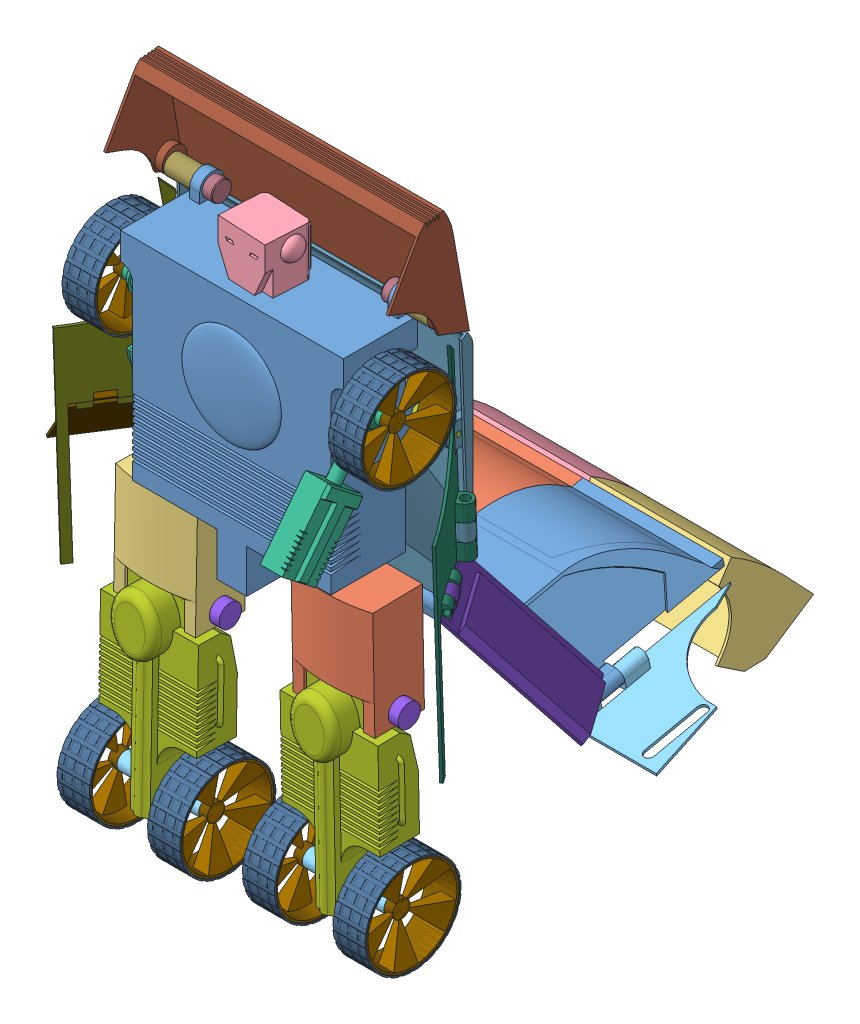
SolidWorks assembly TransformerX_MainAssembly, configuration Default. Lengths in mm.
Overall size (220.06 268.06 212.85).
45 component instances, 25 part files, 124 mates.
Components (placement in the parent):
- Body-1: Body [Default] at (46.3768 50.8704 65.1566) size (90 111.5 41.19)
- Leg2_left-1: Leg2_left [Default] at (81.8768 16.1749 64.6855) x (1 0 0) z (0 -0.019227 0.999815) size (33 44.2 22.31)
- Leg2_right-1: Leg2_right [Default] at (10.8768 16.1749 65.6276) x (1 0 0) z (0 0.019227 0.999815) size (33 44.2 22.31)
- Head-1: Head [Default] at (46.3768 135.8704 65.1566) x (0.998497 0 0.054809) z (-0.054809 0 0.998497) size (26 20 18.29)
- Axis-1: Axis [Default] at (81.8768 8.9762 64.5471) x (0 0 1) z (-1 0 0) size (7 7 39)
- Axis-2: Axis [Default] at (10.8768 8.9762 65.7661) x (0 -0.784262 0.62043) z (-1 0 0) size (7 7 39)
- Arm-4: Arm [Default] at (1.8768 75.0914 61.5517) x (-1 0 0) z (0 0.191408 -0.981511) size (24 60 17)
- Arm-5: Arm [Default] at (90.8768 82.5325 92.8919) x (1 0 0) z (0 0.612187 0.790713) size (24 60 17)
- Leg1-1: Leg1 [Default] at (81.8768 -15.6961 68.0734) x (1 0 0) z (0 -0.019227 0.999815) size (44.5 80.02 25)
- Leg1-2: Leg1 [Default] at (10.8768 -15.5423 70.2383) x (1 0 0) z (0 0.019227 0.999815) size (44.5 80.02 25)
- Axis-3: Axis [Default] at (10.8768 -57.4346 71.0439) x (0 -0.957762 -0.287561) z (-1 0 0) size (7 7 39)
- Axis-4: Axis [Default] at (81.8768 -57.5884 67.2678) x (0 -0.784262 0.62043) z (-1 0 0) size (7 7 39)
- Locker-1: Locker [Default] at (98.3768 8.9762 64.5471) x (0 0.219799 -0.975545) z (1 0 0) size (9 9 4)
- Locker-2: Locker [Default] at (-5.6232 8.9762 65.7661) x (0 -0.568495 0.822687) z (-1 0 0) size (9 9 4)
- Locker-3: Locker [Default] at (27.3768 8.9762 65.7661) x (0 0.855004 -0.518621) z (1 0 0) size (9 9 4)
- Locker-4: Locker [Default] at (65.3768 8.9762 64.5471) x (0 -0.128282 -0.991738) z (-1 0 0) size (9 9 4)
- Wheel-1: Wheel [Default] at (-7.3732 -57.4346 71.0439) x (0 0.703889 0.71031) z (-1 0 0) size (37.5 37.5 12.5)
- Wheel-2: Wheel [Default] at (29.1268 -57.4346 71.0439) x (0 0.151949 0.988388) z (1 0 0) size (37.5 37.5 12.5)
- Wheel-3: Wheel [Default] at (63.6268 -57.5884 67.2678) x (0 -0.151949 -0.988388) z (-1 0 0) size (37.5 37.5 12.5)
- Wheel-4: Wheel [Default] at (100.1268 -57.5884 67.2678) x (0 0.151949 0.988388) z (1 0 0) size (37.5 37.5 12.5)
- Wheel-5: Wheel [Default] at (100.1268 113.3704 69.0166) x (0 0.145658 0.989335) z (1 0 0) size (37.5 37.5 12.5)
- Wheel-6: Wheel [Default] at (-7.3732 113.3704 69.0166) x (0 -0.858748 -0.512398) z (-1 0 0) size (37.5 37.5 12.5)
- Tire-1: Tire [Default] at (63.6268 -57.5884 67.2678) x (0 0.242577 -0.970132) z (1 0 0) size (38.8 38.79 13)
- Tire-2: Tire [Default] at (-7.3732 -57.4346 71.0439) x (0 0.997611 -0.069083) z (1 0 0) size (38.8 38.79 13)
- Tire-3: Tire [Default] at (29.1268 -57.4346 71.0439) x (0 -0.476218 0.879327) z (-1 0 0) size (38.8 38.79 13)
- Tire-4: Tire [Default] at (-7.3732 113.3704 69.0166) x (0 -0.247928 -0.968779) z (1 0 0) size (38.8 38.79 13)
- Tire-5: Tire [Default] at (100.1268 -57.5884 67.2678) x (0 -0.242577 0.970132) z (-1 0 0) size (38.8 38.79 13)
- Tire-6: Tire [Default] at (100.1268 113.3704 69.0166) x (0 0.041073 0.999156) z (-1 0 0) size (38.8 38.79 13)
- CarPart1-1: CarPart1 [Default] at (46.3768 147.7514 56.6059) x (0 0.939693 -0.34202) z (-1 0 0) size (40.79 38 115)
- Axis3-1: Axis3 [Default] at (92.1268 139.8704 50.1566) x (0 0 -1) z (1 0 0) size (8 8 19.5)
- Axis3-2: Axis3 [Default] at (0.6268 139.8704 50.1566) x (0 0.924225 0.381849) z (-1 0 0) size (8 8 19.5)
- Locker2-2: Locker2 [Default] at (10.3768 139.8704 50.1566) x (0 0.082275 0.99661) z (-1 0 0) size (8 8 4)
- Locker2-3: Locker2 [Default] at (82.3768 139.8704 50.1566) x (0 -0.889675 -0.456595) z (1 0 0) size (8 8 4)
- CarPart2-1: CarPart2 [Default] at (46.3768 67.0428 42.5993) x (0 0.999342 0.03628) z (-1 0 0) size (131.64 36.94 126)
- CarPart3_left-1: CarPart3_left [Default] at (119.7728 56.3074 69.5671) x (0 0.999342 0.03628) z (-0.818887 -0.020823 0.573576) size (132.4 36.62 6.5)
- CarPart3_right-1: CarPart3_right [Default] at (-27.0191 56.3074 69.5671) x (0 0.999342 0.03628) z (-0.818887 0.020823 -0.573576) size (132.4 36.62 6.5)
- CarPart_Door_left-1: CarPart_Door_left [Default] at (128.5766 36.22 44.9935) x (-0.579043 0.691915 0.431235) z (-0.579039 -0.721368 0.379924) size (59.5 53.92 22.75)
- CarPart_Door_right-1: CarPart_Door_right [Default] at (-35.2438 35.4986 45.3735) x (0.579041 0.691917 0.431234) z (-0.579041 0.721365 -0.379926) size (59.5 53.92 22.75)
- CarPart4_left-1: CarPart4_left [Default] at (74.6268 -9.0217 -28.6009) x (0 -0.208452 0.978033) z (-1 0 0) size (78.5 35.5 63)
- CarPart4_right-1: CarPart4_right [Default] at (18.1268 -9.0217 -28.6009) x (0 -0.208452 0.978033) z (-1 0 0) size (78.5 35.5 63)
- CarPart5_left-1: CarPart5_left [Default] at (74.6268 -10.0267 -75.1362) x (0 -0.554061 -0.832476) z (1 0 0) size (48.5 32.62 56.5)
- CarPart5_right-1: CarPart5_right [Default] at (18.1268 -10.0267 -75.1362) x (0 -0.554061 -0.832476) z (1 0 0) size (48.5 32.62 56.5)
- CarPart6_left-1: CarPart6_left [Default] at (122.1868 -15.3268 -30.2004) x (0 -0.208452 0.978033) z (0 -0.978033 -0.208452) size (69 37.62 7.5)
- CarPart6_right-1: CarPart6_right [Default] at (-29.4332 -16.3049 -30.4088) x (0 -0.208452 0.978033) z (0 0.978033 0.208452) size (69 37.62 7.5)
- Axis4-1: Axis4 [Default] at (46.3768 97.8704 45.1566) x (0 0 1) z (-1 0 0) size (5.5 5.5 113)
Mates (geometry in assembly coordinates):
- Concentric1: concentric aligned: cylinder of Body-1 through (74.3768 40.6704 65.1566) axis (-1 0 0) radius 3.5; cylinder of Leg2_left-1 through (74.3768 40.6704 65.1566) axis (-1 0 0) radius 3.5
- Coincident1: coincident anti-aligned: plane of Body-1 through (74.3768 40.6704 65.1566) normal (1 0 0); plane of Leg2_left-1 through (74.3768 40.6704 65.1566) normal (-1 0 0)
- Concentric2: concentric aligned: cylinder of Body-1 through (18.3768 40.6704 65.1566) axis (1 0 0) radius 3.5; cylinder of Leg2_right-1 through (18.3768 40.6704 65.1566) axis (1 0 0) radius 3.5
- Coincident2: coincident anti-aligned: plane of Body-1 through (18.3768 40.6704 65.1566) normal (-1 0 0); plane of Leg2_right-1 through (18.3768 40.6704 65.1566) normal (1 0 0)
- Parallel1: parallel aligned: plane of Leg2_left-1 through (65.3768 48.1704 55.1566) normal (0 0 -1); plane of Leg2_right-1 through (-5.6232 48.1704 55.1566) normal (0 0 -1)
- Parallel2: parallel aligned: plane of Body-1 through (91.3768 135.8704 50.1566) normal (0 0 -1); plane of Leg2_right-1
- Concentric3: concentric aligned: cylinder of Body-1 through (46.3768 142.8704 65.1566) axis (0 -1 0) radius 4.5; cylinder of Head-1 through (46.3768 142.8704 65.1566) axis (0 -1 0) radius 4.5
- Coincident5: coincident anti-aligned: plane of Body-1 through (46.3768 142.8704 65.1566) normal (0 1 0); plane of Head-1 through (46.3768 142.8704 65.1566) normal (0 -1 0)
- Parallel3: parallel aligned: plane of Body-1 through (1.3768 135.8704 80.1566) normal (0 0 1); plane of Head-1
- Concentric4: concentric anti-aligned: cylinder of Leg2_right-1 through (27.3768 8.9762 65.7661) axis (-1 0 0) radius 3.5; cylinder of Axis-2 through (32.2535 8.9762 65.7661) axis (1 0 0) radius 3.5
- Coincident7: coincident aligned: plane of Leg2_right-1 through (27.3768 47.9767 55.0142) normal (1 0 0); plane of Axis-2 through (27.3768 7.0156 67.3171) normal (1 0 0)
- Concentric5: concentric anti-aligned: cylinder of Leg2_left-1 through (98.3768 8.9762 64.5471) axis (-1 0 0) radius 3.5; cylinder of Axis-1 through (103.2535 8.9762 64.5471) axis (1 0 0) radius 3.5
- Coincident8: coincident aligned: plane of Leg2_left-1 through (98.3768 48.3612 55.3026) normal (1 0 0); plane of Axis-1 through (98.3768 8.9762 67.0471) normal (1 0 0)
- Concentric6: concentric aligned: cylinder of Body-1 through (77.3768 113.3704 69.0166) axis (1 0 0) radius 3.5; cylinder of Arm-5 through (77.3768 113.3704 69.0166) axis (1 0 0) radius 3.5
- Coincident9: coincident anti-aligned: plane of Body-1 through (86.3768 50.8704 50.1555) normal (1 0 0); plane of Arm-5 through (86.3768 82.5325 92.8919) normal (-1 0 0)
- Concentric7: concentric aligned: cylinder of Body-1 through (15.3768 113.3704 69.0166) axis (-1 0 0) radius 3.5; cylinder of Arm-4 through (15.3768 113.3704 69.0166) axis (-1 0 0) radius 3.5
- Coincident10: coincident anti-aligned: plane of Body-1 through (6.3768 50.8704 50.1555) normal (-1 0 0); plane of Arm-4 through (6.3768 75.0914 61.5517) normal (1 0 0)
- Concentric8: concentric aligned: cylinder of Axis-1 through (103.2535 8.9762 64.5471) axis (1 0 0) radius 3.5; cylinder of Leg1-1 through (62.1258 8.9762 64.5471) axis (1 0 0) radius 3.75
- Coincident11: coincident anti-aligned: plane of Leg2_left-1 through (93.8768 16.1749 64.6855) normal (-1 0 0); plane of Leg1-1 through (93.8768 8.9762 64.5471) normal (1 0 0)
- Concentric9: concentric anti-aligned: cylinder of Axis-2 through (32.2535 8.9762 65.7661) axis (1 0 0) radius 3.5; cylinder of Leg1-2 through (30.6278 8.9762 65.7661) axis (-1 0 0) radius 3.75
- Coincident12: coincident anti-aligned: plane of Leg2_right-1 through (22.8768 16.1749 65.6276) normal (-1 0 0); plane of Leg1-2 through (22.8768 8.9762 65.7661) normal (1 0 0)
- Parallel4: parallel aligned: plane of Leg1-1; plane of Leg1-2
- Parallel5: parallel aligned: plane of Leg2_left-1; plane of Leg1-1
- Concentric10: concentric anti-aligned: cylinder of Leg1-2 through (30.6278 -57.4346 71.0439) axis (-1 0 0) radius 3.5; cylinder of Axis-3 through (32.2535 -57.4346 71.0439) axis (1 0 0) radius 3.5
- Width2: width aligned: plane of Leg1-2 through (14.8768 -62.7797 79.1482) normal (1 0 0); plane of Leg1-2 through (6.8768 -62.7797 79.1482) normal (-1 0 0); plane of Axis-3 through (27.3768 -59.829 70.325) normal (1 0 0); plane of Axis-3 through (-5.6232 -60.7867 70.0374) normal (-1 0 0)
- Concentric11: concentric anti-aligned: cylinder of Leg1-1 through (101.6278 -57.5884 67.2678) axis (-1 0 0) radius 3.5; cylinder of Axis-4 through (103.2535 -57.5884 67.2678) axis (1 0 0) radius 3.5
- Width3: width aligned: plane of Leg1-1 through (77.8768 -63.2412 75.1605) normal (-1 0 0); plane of Leg1-1 through (85.8768 -63.2412 75.1605) normal (1 0 0); plane of Axis-4 through (65.3768 -60.3333 69.4393) normal (-1 0 0); plane of Axis-4 through (98.3768 -59.5491 68.8188) normal (1 0 0)
- Concentric12: concentric aligned: cylinder of Axis-2 through (32.2535 8.9762 65.7661) axis (1 0 0) radius 2.5; cylinder of Locker-2 through (-9.6232 8.9762 65.7661) axis (1 0 0) radius 4.5
- Coincident15: coincident anti-aligned: plane of Leg2_right-1 through (-5.6232 47.9767 55.0142) normal (-1 0 0); plane of Locker-2 through (-5.6232 8.9762 65.7661) normal (1 0 0)
- Concentric13: concentric anti-aligned: cylinder of Axis-1 through (103.2535 8.9762 64.5471) axis (1 0 0) radius 2.5; cylinder of Locker-1 through (102.3768 8.9762 64.5471) axis (-1 0 0) radius 4.5
- Coincident16: coincident anti-aligned: plane of Leg2_left-1 through (98.3768 48.3612 55.3026) normal (1 0 0); plane of Locker-1 through (98.3768 8.9762 64.5471) normal (-1 0 0)
- Concentric14: concentric anti-aligned: cylinder of Axis-2 through (32.2535 8.9762 65.7661) axis (1 0 0) radius 2.5; cylinder of Locker-3 through (31.3768 8.9762 65.7661) axis (-1 0 0) radius 4.5
- Coincident17: coincident anti-aligned: plane of Leg2_right-1 through (27.3768 47.9767 55.0142) normal (1 0 0); plane of Locker-3 through (27.3768 8.9762 65.7661) normal (-1 0 0)
- Concentric15: concentric aligned: cylinder of Axis-1 through (103.2535 8.9762 64.5471) axis (1 0 0) radius 2.5; cylinder of Locker-4 through (62.3768 8.9762 64.5471) axis (1 0 0) radius 2.5
- Coincident18: coincident anti-aligned: plane of Leg2_left-1 through (65.3768 48.3612 55.3026) normal (-1 0 0); plane of Locker-4 through (65.3768 8.9762 64.5471) normal (1 0 0)
- Concentric16: concentric aligned: cylinder of Axis-3 through (32.2535 -57.4346 71.0439) axis (1 0 0) radius 2.5; cylinder of Wheel-1 through (-8.6232 -57.4346 71.0439) axis (1 0 0) radius 2.5
- Coincident19: coincident anti-aligned: plane of Axis-3 through (-5.6232 -60.7867 70.0374) normal (-1 0 0); plane of Wheel-1 through (-5.6232 -59.8982 68.5578) normal (1 0 0)
- Concentric17: concentric anti-aligned: cylinder of Axis-3 through (32.2535 -57.4346 71.0439) axis (1 0 0) radius 2.5; cylinder of Wheel-2 through (30.3768 -57.4346 71.0439) axis (-1 0 0) radius 2.5
- Coincident20: coincident anti-aligned: plane of Axis-3 through (27.3768 -59.829 70.325) normal (1 0 0); plane of Wheel-2 through (27.3768 -57.9664 67.5846) normal (-1 0 0)
- Concentric18: concentric aligned: cylinder of Axis-4 through (103.2535 -57.5884 67.2678) axis (1 0 0) radius 2.5; cylinder of Wheel-3 through (62.3768 -57.5884 67.2678) axis (1 0 0) radius 2.5
- Coincident21: coincident anti-aligned: plane of Axis-4 through (65.3768 -60.3333 69.4393) normal (-1 0 0); plane of Wheel-3 through (65.3768 -57.0566 70.7271) normal (1 0 0)
- Concentric19: concentric anti-aligned: cylinder of Axis-4 through (103.2535 -57.5884 67.2678) axis (1 0 0) radius 2.5; cylinder of Wheel-4 through (101.3768 -57.5884 67.2678) axis (-1 0 0) radius 2.5
- Coincident22: coincident anti-aligned: plane of Axis-4 through (98.3768 -59.5491 68.8188) normal (1 0 0); plane of Wheel-4 through (98.3768 -58.1202 63.8084) normal (-1 0 0)
- Concentric20: concentric aligned: cylinder of Arm-4 through (-8.6232 113.3704 69.0166) axis (1 0 0) radius 2.5; cylinder of Wheel-6 through (-8.6232 113.3704 69.0166) axis (1 0 0) radius 2.5
- Coincident23: coincident anti-aligned: plane of Arm-4 through (-5.6232 113.3704 69.0166) normal (-1 0 0); plane of Wheel-6 through (-5.6232 116.376 70.81) normal (1 0 0)
- Concentric21: concentric aligned: cylinder of Arm-5 through (101.3768 113.3704 69.0166) axis (-1 0 0) radius 2.5; cylinder of Wheel-5 through (101.3768 113.3704 69.0166) axis (-1 0 0) radius 2.5
- Coincident24: coincident anti-aligned: plane of Arm-5 through (98.3768 113.3704 69.0166) normal (1 0 0); plane of Wheel-5 through (98.3768 112.8606 65.5539) normal (-1 0 0)
- Parallel6: parallel aligned: plane of Wheel-3 through (63.6268 -57.0194 67.5637) normal (0 -0.887159 -0.461463); plane of Wheel-4 through (100.1268 -57.0194 67.5637) normal (0 -0.887159 -0.461463)
- Parallel7: parallel aligned: plane of Wheel-1 through (-7.3732 -56.8656 71.3399) normal (0 -0.887159 -0.461463); plane of Wheel-2 through (29.1268 -56.8656 71.3399) normal (0 -0.887159 -0.461463)
- Parallel8: parallel aligned: plane of Wheel-2 through (29.1268 -56.8656 71.3399) normal (0 -0.887159 -0.461463); plane of Wheel-3 through (63.6268 -57.0194 67.5637) normal (0 -0.887159 -0.461463)
- Concentric22: concentric anti-aligned: cylinder of Wheel-1 through (27.7862 -57.4346 71.0439) axis (1 0 0) radius 18.75; cylinder of Tire-2 through (-0.8722 -57.4346 71.0439) axis (-1 0 0) radius 18.75
- Width4: width aligned: plane of Wheel-1 through (-13.6232 -57.4346 71.0439) normal (-1 0 0); plane of Wheel-1 through (-1.1232 -70.6325 57.7256) normal (1 0 0); plane of Tire-2 through (-13.8732 -57.4346 71.0439) normal (-1 0 0); plane of Tire-2 through (-0.8732 -57.4346 71.0439) normal (1 0 0)
- Concentric23: concentric anti-aligned: cylinder of Wheel-2 through (-6.0326 -57.4346 71.0439) axis (-1 0 0) radius 18.75; cylinder of Tire-3 through (22.6258 -57.4346 71.0439) axis (1 0 0) radius 18.75
- Width5: width aligned: plane of Wheel-2 through (35.3768 -57.4346 71.0439) normal (1 0 0); plane of Wheel-2 through (22.8768 -60.2836 52.5116) normal (-1 0 0); plane of Tire-3 through (35.6268 -57.4346 71.0439) normal (1 0 0); plane of Tire-3 through (22.6268 -57.4346 71.0439) normal (-1 0 0)
- Concentric24: concentric anti-aligned: cylinder of Wheel-3 through (98.7862 -57.5884 67.2678) axis (1 0 0) radius 18.75; cylinder of Tire-1 through (70.1278 -57.5884 67.2678) axis (-1 0 0) radius 18.75
- Width6: width aligned: plane of Wheel-3 through (69.8768 -54.7394 85.8) normal (1 0 0); plane of Wheel-3 through (57.3768 -57.5884 67.2678) normal (-1 0 0); plane of Tire-1 through (70.1268 -57.5884 67.2678) normal (1 0 0); plane of Tire-1 through (57.1268 -57.5884 67.2678) normal (-1 0 0)
- Concentric25: concentric anti-aligned: cylinder of Wheel-4 through (64.9674 -57.5884 67.2678) axis (-1 0 0) radius 18.75; cylinder of Tire-5 through (93.6258 -57.5884 67.2678) axis (1 0 0) radius 18.75
- Width7: width aligned: plane of Wheel-4 through (93.8768 -60.4374 48.7355) normal (-1 0 0); plane of Wheel-4 through (106.3768 -57.5884 67.2678) normal (1 0 0); plane of Tire-5 through (93.6268 -57.5884 67.2678) normal (-1 0 0); plane of Tire-5 through (106.6268 -57.5884 67.2678) normal (1 0 0)
- Concentric26: concentric anti-aligned: cylinder of Wheel-6 through (27.7862 113.3704 69.0166) axis (1 0 0) radius 18.75; cylinder of Tire-4 through (-0.8722 113.3704 69.0166) axis (-1 0 0) radius 18.75
- Concentric27: concentric anti-aligned: cylinder of Wheel-5 through (64.9674 113.3704 69.0166) axis (-1 0 0) radius 18.75; cylinder of Tire-6 through (93.6258 113.3704 69.0166) axis (1 0 0) radius 18.75
- Width8: width anti-aligned: plane of Wheel-5 through (106.3768 113.3704 69.0166) normal (1 0 0); plane of Wheel-5 through (93.8768 110.6393 50.4665) normal (-1 0 0); plane of Tire-6 through (93.6268 113.3704 69.0166) normal (-1 0 0); plane of Tire-6 through (106.6268 113.3704 69.0166) normal (1 0 0)
- Width9: width aligned: plane of Wheel-6 through (-13.6232 113.3704 69.0166) normal (-1 0 0); plane of Wheel-6 through (-1.1232 129.4719 78.624) normal (1 0 0); plane of Tire-4 through (-13.8732 113.3704 69.0166) normal (-1 0 0); plane of Tire-4 through (-0.8732 113.3704 69.0166) normal (1 0 0)
- Parallel9: parallel aligned: plane of Wheel-4 through (100.1268 -57.0171 67.5593) normal (0 -0.8907 -0.454592); plane of Tire-5 through (100.1268 -57.5884 67.2678) normal (0 -0.8907 -0.454592)
- Parallel10: parallel aligned: plane of Wheel-3 through (63.6268 -57.0171 67.5593) normal (0 -0.8907 -0.454592); plane of Tire-1 through (63.6268 -57.5884 67.2678) normal (0 -0.8907 -0.454592)
- Parallel11: parallel aligned: plane of Wheel-2 through (29.1268 -56.8633 71.3355) normal (0 -0.8907 -0.454592); plane of Tire-3 through (29.1268 -57.4346 71.0439) normal (0 -0.8907 -0.454592)
- Parallel12: parallel aligned: plane of Wheel-1 through (-7.3732 -57.5353 71.6773) normal (0 0.157101 -0.987582); plane of Tire-2 through (-7.3732 -57.4346 71.0439) normal (0 0.157101 -0.987582)
- Parallel13: parallel aligned: plane of Wheel-5 through (100.1268 113.0877 68.4409) normal (0 0.440785 0.897613); plane of Tire-6 through (100.1268 113.3704 69.0166) normal (0 0.440785 0.897613)
- Parallel14: parallel anti-aligned: plane of Wheel-6 through (-7.3732 112.7455 68.8718) normal (0 0.974193 0.225718); plane of Tire-4 through (-7.3732 113.3704 69.0166) normal (0 -0.974193 -0.225718)
- Concentric28: concentric anti-aligned: cylinder of Body-1 through (1.3058 139.8704 50.1566) axis (1 0 0) radius 2.5; cylinder of CarPart1-1 through (101.8768 139.8704 50.1566) axis (-1 0 0) radius 2.5
- Width10: width anti-aligned: plane of Body-1 through (91.3768 135.8704 80.1566) normal (1 0 0); plane of Body-1 through (1.3768 135.8704 50.1566) normal (-1 0 0); plane of CarPart1-1 through (-11.1232 132.7018 73.7335) normal (-1 0 0); plane of CarPart1-1 through (103.8768 132.7018 73.7335) normal (1 0 0)
- Concentric30: concentric aligned: cylinder of CarPart1-1 through (101.8768 139.8704 50.1566) axis (-1 0 0) radius 2.5; cylinder of Axis3-1 through (63.5942 139.8704 50.1566) axis (-1 0 0) radius 2.5
- Coincident36: coincident anti-aligned: plane of Body-1 through (88.3768 139.8704 50.1566) normal (1 0 0); plane of Axis3-1 through (88.3768 139.8704 47.6566) normal (-1 0 0)
- Concentric31: concentric anti-aligned: cylinder of Body-1 through (15.4479 139.8704 50.1566) axis (-1 0 0) radius 2.5; cylinder of Axis3-2 through (29.1595 139.8704 50.1566) axis (1 0 0) radius 2.5
- Coincident37: coincident anti-aligned: plane of CarPart1-1 through (-7.1232 140.998 49.7461) normal (1 0 0); plane of Axis3-2 through (-7.1232 143.5673 51.684) normal (-1 0 0)
- Concentric32: concentric anti-aligned: cylinder of Axis3-2 through (29.1595 139.8704 50.1566) axis (1 0 0) radius 2.5; cylinder of Locker2-2 through (10.3768 139.8704 50.1566) axis (-1 0 0) radius 2.5
- Coincident38: coincident anti-aligned: plane of Body-1 through (8.3768 139.8704 50.1566) normal (1 0 0); plane of Locker2-2 through (8.3768 139.8704 50.1566) normal (-1 0 0)
- Concentric34: concentric aligned: cylinder of Locker2-3 through (-59.0523 139.8704 50.1566) axis (-1 0 0) radius 4; cylinder of Axis3-1 through (63.5942 139.8704 50.1566) axis (-1 0 0) radius 2.5
- Coincident39: coincident anti-aligned: plane of Body-1 through (84.3768 139.8704 50.1566) normal (-1 0 0); plane of Locker2-3 through (84.3768 139.8704 50.1566) normal (1 0 0)
- Parallel15: parallel aligned: plane of Body-1 through (91.3768 135.8704 50.1566) normal (0 0 -1); plane of CarPart2-1 through (174.8356 127.4919 40.4312) normal (0 0 -1)
- Width12: width anti-aligned: plane of Body-1 through (86.3768 50.8704 50.1555) normal (1 0 0); plane of Body-1 through (6.3768 50.8704 50.1555) normal (-1 0 0); plane of CarPart2-1 through (-11.1232 133.3218 43.0042) normal (-1 0 0); plane of CarPart2-1 through (103.8768 67.1154 40.6006) normal (1 0 0)
- Concentric36: concentric aligned: cylinder of CarPart2-1 through (106.3768 75.8779 45.922) axis (0 -0.999342 -0.03628) radius 1.75; cylinder of CarPart3_left-1 through (106.3768 82.6234 46.1669) axis (0 -0.999342 -0.03628) radius 1.75
- Coincident42: coincident anti-aligned: plane of CarPart2-1 through (106.3768 70.9314 45.7424) normal (0 0.999342 0.03628); plane of CarPart3_left-1 through (106.3768 70.9314 45.7424) normal (0 -0.999342 -0.03628)
- Concentric37: concentric aligned: cylinder of CarPart2-1 through (-13.6232 75.8779 45.922) axis (0 -0.999342 -0.03628) radius 1.75; cylinder of CarPart3_right-1 through (-13.6232 82.6234 46.1669) axis (0 -0.999342 -0.03628) radius 1.75
- Coincident43: coincident anti-aligned: plane of CarPart2-1 through (-13.6232 63.936 45.4885) normal (0 -0.999342 -0.03628); plane of CarPart3_right-1 through (-13.6232 63.936 45.4885) normal (0 0.999342 0.03628)
- Concentric38: concentric aligned: cylinder of CarPart3_right-1 through (-32.0187 56.1687 73.3874) axis (0.573954 0.029709 -0.818348) radius 1.25; cylinder of CarPart_Door_right-1 through (-27.7345 56.3905 67.2789) axis (0.573954 0.029709 -0.818348) radius 1.25
- Coincident46: coincident anti-aligned: plane of CarPart3_right-1 through (-20.5411 56.6743 59.4601) normal (-0.573954 -0.029709 0.818348); plane of CarPart_Door_right-1 through (-20.8769 55.6935 59.189) normal (0.573954 0.029709 -0.818348)
- Parallel16: parallel aligned: plane of Body-1 through (6.3768 50.8704 50.1555) normal (-1 0 0); plane of CarPart3_right-1
- Concentric39: concentric anti-aligned: cylinder of CarPart3_left-1 through (109.5422 56.957 51.6721) axis (0.573954 -0.029709 0.818348) radius 1.25; cylinder of CarPart_Door_left-1 through (120.4881 56.3905 67.2789) axis (-0.573954 0.029709 -0.818348) radius 1.25
- Coincident47: coincident anti-aligned: plane of CarPart3_left-1 through (113.2948 56.6743 59.4601) normal (0.573954 -0.029709 0.818348); plane of CarPart_Door_left-1 through (113.0515 54.9722 59.5689) normal (-0.573954 0.029709 -0.818348)
- Parallel17: parallel aligned: plane of Body-1 through (86.3768 50.8704 50.1555) normal (1 0 0); plane of CarPart3_left-1
- Parallel18: parallel aligned: plane of CarPart3_left-1; plane of CarPart_Door_left-1
- Parallel19: parallel aligned: plane of CarPart3_right-1; plane of CarPart_Door_right-1
- Concentric40: concentric aligned: cylinder of CarPart2-1 through (14.3058 6.7583 14.8939) axis (1 0 0) radius 2.5; cylinder of CarPart4_left-1 through (54.3058 6.7583 14.8939) axis (1 0 0) radius 2.5
- Coincident50: coincident anti-aligned: plane of CarPart2-1 through (61.3768 6.7583 14.8939) normal (1 0 0); plane of CarPart4_left-1 through (61.3768 6.7583 14.8939) normal (-1 0 0)
- Concentric41: concentric aligned: cylinder of CarPart2-1 through (28.4479 6.7583 14.8939) axis (-1 0 0) radius 2.5; cylinder of CarPart4_right-1 through (38.4479 6.7583 14.8939) axis (-1 0 0) radius 2.5
- Coincident51: coincident anti-aligned: plane of CarPart2-1 through (31.3768 6.7583 14.8939) normal (-1 0 0); plane of CarPart4_right-1 through (31.3768 6.7583 14.8939) normal (1 0 0)
- Parallel20: parallel aligned: plane of CarPart2-1 through (46.3768 -98.4436 14.577) normal (0 0.03628 -0.999342); plane of CarPart4_left-1
- Parallel33: parallel aligned: plane of CarPart2-1 through (46.3768 -98.4436 14.577) normal (0 0.03628 -0.999342); plane of CarPart4_right-1
- Concentric42: concentric anti-aligned: cylinder of CarPart4_right-1 through (6.6168 -2.9645 -61.818) axis (-1 0 0) radius 0.35; cylinder of CarPart5_right-1 through (-0.3631 -2.9645 -61.818) axis (1 0 0) radius 0.35
- Coincident55: coincident anti-aligned: plane of CarPart4_right-1 through (0.6268 -2.9645 -61.818) normal (-1 0 0); plane of CarPart5_right-1 through (0.6268 -2.9645 -61.818) normal (1 0 0)
- Concentric43: concentric anti-aligned: cylinder of CarPart4_left-1 through (61.1369 -2.9645 -61.818) axis (1 0 0) radius 0.35; cylinder of CarPart5_left-1 through (58.1168 -2.9645 -61.818) axis (-1 0 0) radius 0.35
- Coincident56: coincident anti-aligned: plane of CarPart4_left-1 through (92.1268 -2.9645 -61.818) normal (1 0 0); plane of CarPart5_left-1 through (92.1268 -2.9645 -61.818) normal (-1 0 0)
- Parallel21: parallel anti-aligned: plane of CarPart4_left-1; plane of CarPart5_left-1
- Parallel22: parallel aligned: plane of CarPart5_left-1 through (136.8768 -7.8714 -77.4147) normal (0 0.687196 -0.726472); plane of CarPart5_right-1 through (80.3768 -7.8714 -77.4147) normal (0 0.687196 -0.726472)
- Concentric45: concentric anti-aligned: cylinder of CarPart4_right-1 through (-13.6232 -18.0426 -0.668) axis (0 0.208452 -0.978033) radius 1.75; cylinder of CarPart6_right-1 through (-13.6232 -11.81 -29.9107) axis (0 -0.208452 0.978033) radius 1.75
- Coincident59: coincident anti-aligned: plane of CarPart4_right-1 through (-13.6232 -14.9263 -15.2893) normal (0 0.208452 -0.978033); plane of CarPart6_right-1 through (-13.6232 -14.9263 -15.2893) normal (0 -0.208452 0.978033)
- Concentric46: concentric aligned: cylinder of CarPart4_left-1 through (106.3768 -13.8945 -20.1303) axis (0 -0.208452 0.978033) radius 1.75; cylinder of CarPart6_left-1 through (106.3768 -11.81 -29.9107) axis (0 -0.208452 0.978033) radius 1.75
- Coincident60: coincident anti-aligned: plane of CarPart4_left-1 through (106.3768 -14.9263 -15.2893) normal (0 0.208452 -0.978033); plane of CarPart6_left-1 through (106.3768 -14.9263 -15.2893) normal (0 -0.208452 0.978033)
- LimitAngle1: limit planar angle = 0.785398 rad aligned: plane of CarPart_Door_right-1 through (-18.6269 53.3857 44.7977) normal (-0.579041 0.721365 -0.379926); plane of CarPart3_right-1 through (-27.4286 111.8689 71.297) normal (-0.818887 0.020823 -0.573576)
- Parallel24: parallel aligned: plane of CarPart_Door_left-1; plane of CarPart6_left-1
- GearMate1: gear = 2.5 : 2.5 mm: circle of CarPart_Door_right-1; circle of CarPart_Door_left-1
- GearMate4: gear = 3.5 : 3.5 mm: cylinder of CarPart3_left-1 through (106.3768 82.6234 46.1669) axis (0 -0.999342 -0.03628) radius 1.75; cylinder of CarPart3_right-1 through (-13.6232 82.6234 46.1669) axis (0 -0.999342 -0.03628) radius 1.75
- LimitAngle2: limit planar angle = 0.959931 rad aligned: plane of CarPart3_right-1 through (-27.4286 111.8689 71.297) normal (-0.818887 0.020823 -0.573576); plane of CarPart2-1 through (174.8356 127.4919 40.4312) normal (0 0 -1)
- LimitAngle3: limit planar angle = 0 rad aligned: plane of CarPart6_right-1 through (-44.2122 -10.0977 -54.7349) normal (0 0.978033 0.208452); plane of CarPart4_right-1 through (-76.4606 4.3775 9.2742) normal (0 0.978033 0.208452)
- GearMate12: gear = 3.5 : 3.5 mm: cylinder of CarPart6_right-1 through (-13.6232 -11.81 -29.9107) axis (0 -0.208452 0.978033) radius 1.75; cylinder of CarPart6_left-1 through (106.3768 -11.81 -29.9107) axis (0 -0.208452 0.978033) radius 1.75
- GearMate10: gear = 7 : 3.5 mm: cylinder of CarPart6_right-1 through (-13.6232 -33.1442 42.4624) axis (0 0.999999 -0.001715) radius 1.75; cylinder of CarPart2-1 through (28.4479 6.7583 14.8939) axis (-1 0 0) radius 2.5
- Parallel40: parallel aligned: plane of CarPart4_left-1 through (-19.9606 4.3775 9.2742) normal (0 0.978033 0.208452); plane of CarPart4_right-1 through (-76.4606 4.3775 9.2742) normal (0 0.978033 0.208452)
- GearMate17: gear = 7 : 7 mm: cylinder of Leg2_right-1 through (18.3768 40.6704 65.1566) axis (1 0 0) radius 3.5; cylinder of Leg2_left-1 through (74.3768 40.6704 65.1566) axis (-1 0 0) radius 3.5
- LimitAngle4: limit planar angle = 0 rad aligned: plane of Leg1-2 through (-3.1232 -44.983 78.8059) normal (0 0.019227 0.999815); plane of Leg2_right-1 through (-1.1232 4.1694 75.8604) normal (0 0.019227 0.999815)
- LimitAngle5: limit planar angle = 0 rad aligned: plane of Leg1-1 through (67.8768 -45.4445 75.5028) normal (0 -0.019227 0.999815); plane of Leg2_left-1 through (69.8768 3.7849 74.4491) normal (0 -0.019227 0.999815)
- LimitAngle6: limit planar angle = 0.174533 rad aligned: plane of CarPart1-1 through (-11.1232 170.3041 48.3974) normal (0 0.173648 -0.984808); plane of CarPart2-1 through (174.8356 127.4919 40.4312) normal (0 0 -1)
- Concentric47: concentric anti-aligned: cylinder of Body-1 through (93.4479 97.8704 45.1566) axis (-1 0 0) radius 2.5; cylinder of Axis4-1 through (117.7908 97.8704 45.1566) axis (1 0 0) radius 2.5
- Coincident61: coincident aligned: plane of CarPart2-1 through (102.8768 97.8704 45.1566) normal (1 0 0); plane of Axis4-1 through (102.8768 97.8704 46.1716) normal (1 0 0)
- Concentric48: concentric anti-aligned: cone of CarPart2-1 through (-7.1232 97.8704 45.1566) axis (-1 0 0); cylinder of Axis4-1 through (117.7908 97.8704 45.1566) axis (1 0 0) radius 2.5
